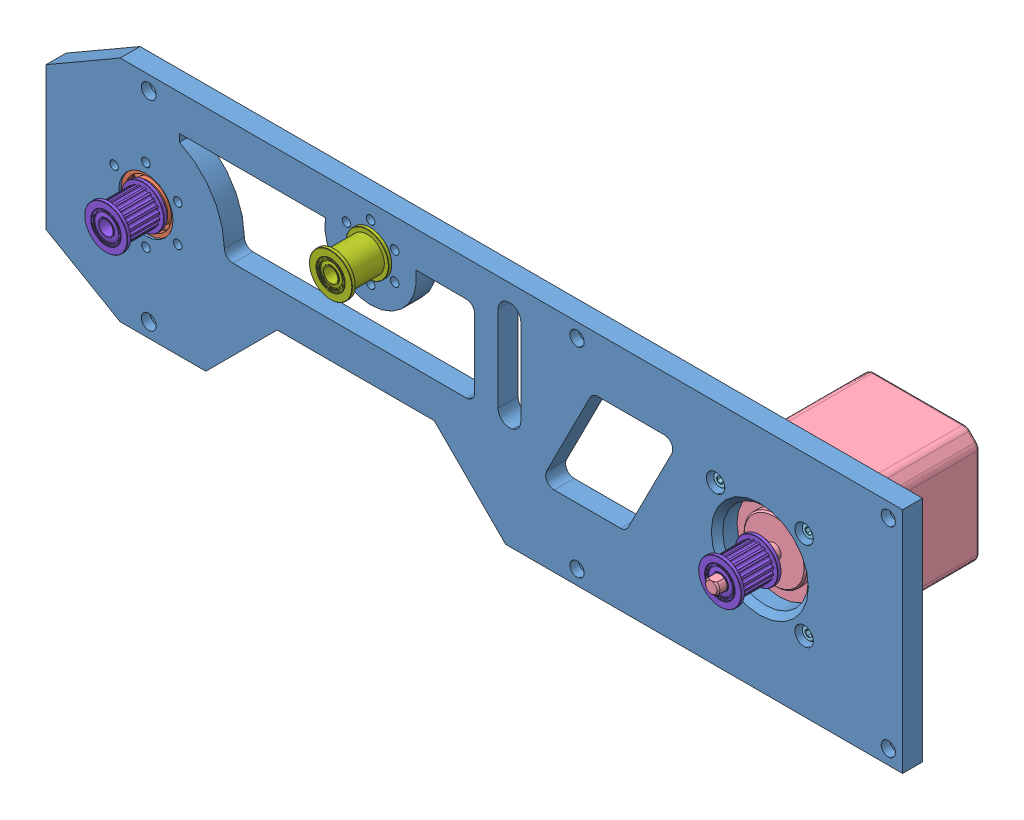
SolidWorks assembly Assem1, configuration Default. Lengths in mm.
Overall size (300 80 73).
17 component instances, 8 part files, 33 mates.
Components (placement in the parent):
- UpperSecV2-1: UpperSecV2 [Default] at (15.2169 151.3995 284.8408) size (300 80 7)
- 5972K91_Ball Bearing-1: 5972K91_Ball Bearing [5972K91] at (50.2169 191.3995 287.5408) x (0.994176 -0.107767 0) z (0 0 1) size (22 22 7)
- 7804K117_Stainless Steel Ball Bearing (1)-1: 7804K117_Stainless Steel Ball Bearing (1) [7804K117] at (128.9085 216.3995 287.5408) size (16 16 5)
- Nema17(SY42STH47-1684A)singelshaft.step-1: Nema17(SY42STH47-1684A)singelshaft.step [Default] at (265.2169 191.3995 260.3408) size (42 44 73)
- 91290A053_Black-Oxide Alloy Steel Socket Head Screw-1: 91290A053_Black-Oxide Alloy Steel Socket Head Screw [91290A053] at (249.7169 206.8995 282.0908) x (0.894964 0.446138 0) z (0 0 1) size (4.5 4.5 16.62)
- 91290A053_Black-Oxide Alloy Steel Socket Head Screw-2: 91290A053_Black-Oxide Alloy Steel Socket Head Screw [91290A053] at (280.7169 206.8995 282.0908) x (0.999992 -0.003919 0) z (0 0 1) size (4.5 4.5 16.62)
- 91290A053_Black-Oxide Alloy Steel Socket Head Screw-3: 91290A053_Black-Oxide Alloy Steel Socket Head Screw [91290A053] at (249.7169 175.8995 282.0908) x (0.465304 -0.885151 0) z (0 0 1) size (4.5 4.5 16.62)
- 91290A053_Black-Oxide Alloy Steel Socket Head Screw-4: 91290A053_Black-Oxide Alloy Steel Socket Head Screw [91290A053] at (280.7169 175.8995 282.0908) x (0.996146 0.087715 0) z (0 0 1) size (4.5 4.5 16.62)
- 97763A811_18-8 Stainless Steel Button Head Hex Drive Screws-1: 97763A811_18-8 Stainless Steel Button Head Hex Drive Screws [97763A811] at (120.4648 221.2745 283.3908) x (-0.921018 -0.389521 0) z (0 0 -1) size (5.7 5.7 6.94)
- 97763A811_18-8 Stainless Steel Button Head Hex Drive Screws-2: 97763A811_18-8 Stainless Steel Button Head Hex Drive Screws [97763A811] at (120.4648 211.5245 283.3908) x (-0.206609 -0.978424 0) z (0 0 -1) size (5.7 5.7 6.94)
- 97763A811_18-8 Stainless Steel Button Head Hex Drive Screws-3: 97763A811_18-8 Stainless Steel Button Head Hex Drive Screws [97763A811] at (128.9085 206.6495 283.3908) x (-0.380121 -0.924937 0) z (0 0 -1) size (5.7 5.7 6.94)
- 97763A811_18-8 Stainless Steel Button Head Hex Drive Screws-4: 97763A811_18-8 Stainless Steel Button Head Hex Drive Screws [97763A811] at (128.9085 226.1495 283.3908) x (-0.830871 -0.556465 0) z (0 0 -1) size (5.7 5.7 6.94)
- 97763A811_18-8 Stainless Steel Button Head Hex Drive Screws-5: 97763A811_18-8 Stainless Steel Button Head Hex Drive Screws [97763A811] at (137.3523 221.2745 283.3908) x (-0.893833 -0.448399 0) z (0 0 -1) size (5.7 5.7 6.94)
- 97763A811_18-8 Stainless Steel Button Head Hex Drive Screws-6: 97763A811_18-8 Stainless Steel Button Head Hex Drive Screws [97763A811] at (137.3523 211.5245 283.3908) x (-0.82834 0.560226 0) z (0 0 -1) size (5.7 5.7 6.94)
- 3693N15_High-Strength HTD Timing Belt Idler Pulley-1: 3693N15_High-Strength HTD Timing Belt Idler Pulley [3693N15] at (128.9085 216.3995 298.8408) x (0.99941 -0.03434 0) z (0 0 1) size (15 15 14)
- 3693N12_High-Strength HTD Timing Belt Idler Pulley-1: 3693N12_High-Strength HTD Timing Belt Idler Pulley [3693N12] at (265.2169 191.3995 298.8408) size (15 15 14)
- 3693N12_High-Strength HTD Timing Belt Idler Pulley-2: 3693N12_High-Strength HTD Timing Belt Idler Pulley [3693N12] at (50.2169 191.3995 298.8408) x (0.999929 0.011945 0) z (0 0 1) size (15 15 14)
Mates (geometry in assembly coordinates):
- Concentric1: concentric aligned: cylinder of UpperSecV2-1 through (50.2169 191.3995 281.8408) axis (0 0 1) radius 11; cylinder of 5972K91_Ball Bearing-1 through (50.2169 191.3995 291.0408) axis (0 0 1) radius 11
- Coincident1: coincident anti-aligned: plane of UpperSecV2-1 through (50.2169 191.3995 291.0408) normal (0 0 -1); plane of 5972K91_Ball Bearing-1 through (51.3646 201.9875 291.0408) normal (0 0 1)
- Concentric2: concentric aligned: cylinder of UpperSecV2-1 through (128.9085 216.3995 284.8408) axis (0 0 1) radius 8; cylinder of 7804K117_Stainless Steel Ball Bearing (1)-1 through (128.9085 216.3995 290.0408) axis (0 0 1) radius 8
- Coincident2: coincident anti-aligned: plane of UpperSecV2-1 through (128.9085 216.3995 290.0408) normal (0 0 -1); plane of 7804K117_Stainless Steel Ball Bearing (1)-1 through (128.9085 224.1495 290.0408) normal (0 0 1)
- Concentric3: concentric anti-aligned: cylinder of UpperSecV2-1 through (265.2169 191.3995 284.8408) axis (0 0 1) radius 15; cylinder of Nema17(SY42STH47-1684A)singelshaft.step-1 through (265.2169 191.3995 286.8408) axis (0 0 -1) radius 11
- Concentric4: concentric aligned: cylinder of UpperSecV2-1 through (280.7169 206.8995 284.8408) axis (0 0 1) radius 1.75; cylinder of Nema17(SY42STH47-1684A)singelshaft.step-1 through (280.7169 206.8995 284.8408) axis (0 0 1) radius 1.25
- Coincident3: coincident anti-aligned: plane of UpperSecV2-1 through (15.2169 151.3995 284.8408) normal (0 0 -1); plane of Nema17(SY42STH47-1684A)singelshaft.step-1 through (265.2169 191.3995 284.8408) normal (0 0 1)
- Concentric6: concentric anti-aligned: cylinder of UpperSecV2-1 through (249.7169 206.8995 284.8408) axis (0 0 1) radius 1.75; cylinder of 91290A053_Black-Oxide Alloy Steel Socket Head Screw-1 through (249.7169 206.8995 273.8408) axis (0 0 -1) radius 2.25
- Coincident5: coincident anti-aligned: plane of UpperSecV2-1 through (249.7169 206.8995 287.8408) normal (0 0 1); plane of 91290A053_Black-Oxide Alloy Steel Socket Head Screw-1 through (247.8151 205.9515 287.8408) normal (0 0 -1)
- Concentric7: concentric anti-aligned: cylinder of UpperSecV2-1 through (280.7169 206.8995 287.8408) axis (0 0 1) radius 3.25; cylinder of 91290A053_Black-Oxide Alloy Steel Socket Head Screw-2 through (280.7169 206.8995 273.8408) axis (0 0 -1) radius 2.25
- Coincident6: coincident anti-aligned: plane of UpperSecV2-1 through (280.7169 206.8995 287.8408) normal (0 0 1); plane of 91290A053_Black-Oxide Alloy Steel Socket Head Screw-2 through (278.5919 206.9079 287.8408) normal (0 0 -1)
- Concentric8: concentric anti-aligned: cylinder of UpperSecV2-1 through (249.7169 175.8995 287.8408) axis (0 0 1) radius 3.25; cylinder of 91290A053_Black-Oxide Alloy Steel Socket Head Screw-3 through (249.7169 175.8995 273.8408) axis (0 0 -1) radius 2.25
- Coincident7: coincident anti-aligned: plane of UpperSecV2-1 through (249.7169 175.8995 287.8408) normal (0 0 1); plane of 91290A053_Black-Oxide Alloy Steel Socket Head Screw-3 through (248.7281 177.7805 287.8408) normal (0 0 -1)
- Concentric9: concentric anti-aligned: cylinder of UpperSecV2-1 through (280.7169 175.8995 287.8408) axis (0 0 1) radius 3.25; cylinder of 91290A053_Black-Oxide Alloy Steel Socket Head Screw-4 through (280.7169 175.8995 273.8408) axis (0 0 -1) radius 2.25
- Coincident8: coincident anti-aligned: plane of UpperSecV2-1 through (280.7169 175.8995 287.8408) normal (0 0 1); plane of 91290A053_Black-Oxide Alloy Steel Socket Head Screw-4 through (278.6001 175.7131 287.8408) normal (0 0 -1)
- Concentric11: concentric aligned: cylinder of UpperSecV2-1 through (120.4648 211.5245 291.8408) axis (0 0 -1) radius 1.5; cylinder of 97763A811_18-8 Stainless Steel Button Head Hex Drive Screws-2 through (120.4648 211.5245 283.3908) axis (0 0 -1) radius 2.85
- Coincident10: coincident anti-aligned: plane of 7804K117_Stainless Steel Ball Bearing (1)-1 through (128.9085 224.1495 285.0408) normal (0 0 -1); plane of 97763A811_18-8 Stainless Steel Button Head Hex Drive Screws-2 through (123.2533 210.9357 285.0408) normal (0 0 1)
- Concentric12: concentric aligned: cylinder of UpperSecV2-1 through (120.4648 221.2745 291.8408) axis (0 0 -1) radius 1.5; cylinder of 97763A811_18-8 Stainless Steel Button Head Hex Drive Screws-1 through (120.4648 221.2745 283.3908) axis (0 0 -1) radius 2.85
- Coincident11: coincident anti-aligned: plane of 7804K117_Stainless Steel Ball Bearing (1)-1 through (128.9085 224.1495 285.0408) normal (0 0 -1); plane of 97763A811_18-8 Stainless Steel Button Head Hex Drive Screws-1 through (121.5749 218.6496 285.0408) normal (0 0 1)
- Concentric13: concentric aligned: cylinder of UpperSecV2-1 through (128.9085 206.6495 291.8408) axis (0 0 -1) radius 1.5; cylinder of 97763A811_18-8 Stainless Steel Button Head Hex Drive Screws-3 through (128.9085 206.6495 283.3908) axis (0 0 -1) radius 2.85
- Coincident12: coincident anti-aligned: plane of 7804K117_Stainless Steel Ball Bearing (1)-1 through (128.9085 224.1495 285.0408) normal (0 0 -1); plane of 97763A811_18-8 Stainless Steel Button Head Hex Drive Screws-3 through (131.5446 205.5662 285.0408) normal (0 0 1)
- Concentric14: concentric aligned: cylinder of UpperSecV2-1 through (137.3523 211.5245 291.8408) axis (0 0 -1) radius 1.5; cylinder of 97763A811_18-8 Stainless Steel Button Head Hex Drive Screws-6 through (137.3523 211.5245 283.3908) axis (0 0 -1) radius 2.85
- Coincident13: coincident anti-aligned: plane of 7804K117_Stainless Steel Ball Bearing (1)-1 through (128.9085 224.1495 285.0408) normal (0 0 -1); plane of 97763A811_18-8 Stainless Steel Button Head Hex Drive Screws-6 through (135.7556 209.1638 285.0408) normal (0 0 1)
- Concentric15: concentric aligned: cylinder of UpperSecV2-1 through (137.3523 221.2745 291.8408) axis (0 0 -1) radius 1.5; cylinder of 97763A811_18-8 Stainless Steel Button Head Hex Drive Screws-5 through (137.3523 221.2745 283.3908) axis (0 0 -1) radius 2.85
- Coincident14: coincident anti-aligned: plane of 7804K117_Stainless Steel Ball Bearing (1)-1 through (128.9085 224.1495 285.0408) normal (0 0 -1); plane of 97763A811_18-8 Stainless Steel Button Head Hex Drive Screws-5 through (138.6302 218.7271 285.0408) normal (0 0 1)
- Concentric16: concentric aligned: cylinder of UpperSecV2-1 through (128.9085 226.1495 291.8408) axis (0 0 -1) radius 1.5; cylinder of 97763A811_18-8 Stainless Steel Button Head Hex Drive Screws-4 through (128.9085 226.1495 283.3908) axis (0 0 -1) radius 2.85
- Coincident15: coincident anti-aligned: plane of 7804K117_Stainless Steel Ball Bearing (1)-1 through (128.9085 224.1495 285.0408) normal (0 0 -1); plane of 97763A811_18-8 Stainless Steel Button Head Hex Drive Screws-4 through (130.4944 223.7816 285.0408) normal (0 0 1)
- Concentric17: concentric aligned: cylinder of 7804K117_Stainless Steel Ball Bearing (1)-1 through (128.9085 216.3995 290.0408) axis (0 0 1) radius 4; cylinder of 3693N15_High-Strength HTD Timing Belt Idler Pulley-1 through (128.9085 216.3995 305.8408) axis (0 0 1) radius 2.5
- Coincident16: coincident anti-aligned: plane of UpperSecV2-1 through (15.2169 151.3995 291.8408) normal (0 0 1); plane of 3693N15_High-Strength HTD Timing Belt Idler Pulley-1 through (129.1661 223.8951 291.8408) normal (0 0 -1)
- Concentric18: concentric: cylinder of Nema17(SY42STH47-1684A)singelshaft.step-1 through (265.2169 191.3995 308.8408) axis (0 0 -1) radius 2.5; cylinder of 3693N12_High-Strength HTD Timing Belt Idler Pulley-1 through (265.2169 191.3995 305.8408) axis (0 0 1) radius 2.5
- Coincident17: coincident anti-aligned: plane of UpperSecV2-1 through (15.2169 151.3995 291.8408) normal (0 0 1); plane of 3693N12_High-Strength HTD Timing Belt Idler Pulley-1 through (265.2169 198.8995 291.8408) normal (0 0 -1)
- Concentric19: concentric aligned: cylinder of 5972K91_Ball Bearing-1 through (50.2169 191.3995 291.0408) axis (0 0 1) radius 4; cylinder of 3693N12_High-Strength HTD Timing Belt Idler Pulley-2 through (50.2169 191.3995 305.8408) axis (0 0 1) radius 2.5
- Coincident18: coincident anti-aligned: plane of UpperSecV2-1 through (15.2169 151.3995 291.8408) normal (0 0 1); plane of 3693N12_High-Strength HTD Timing Belt Idler Pulley-2 through (50.1273 198.899 291.8408) normal (0 0 -1)
